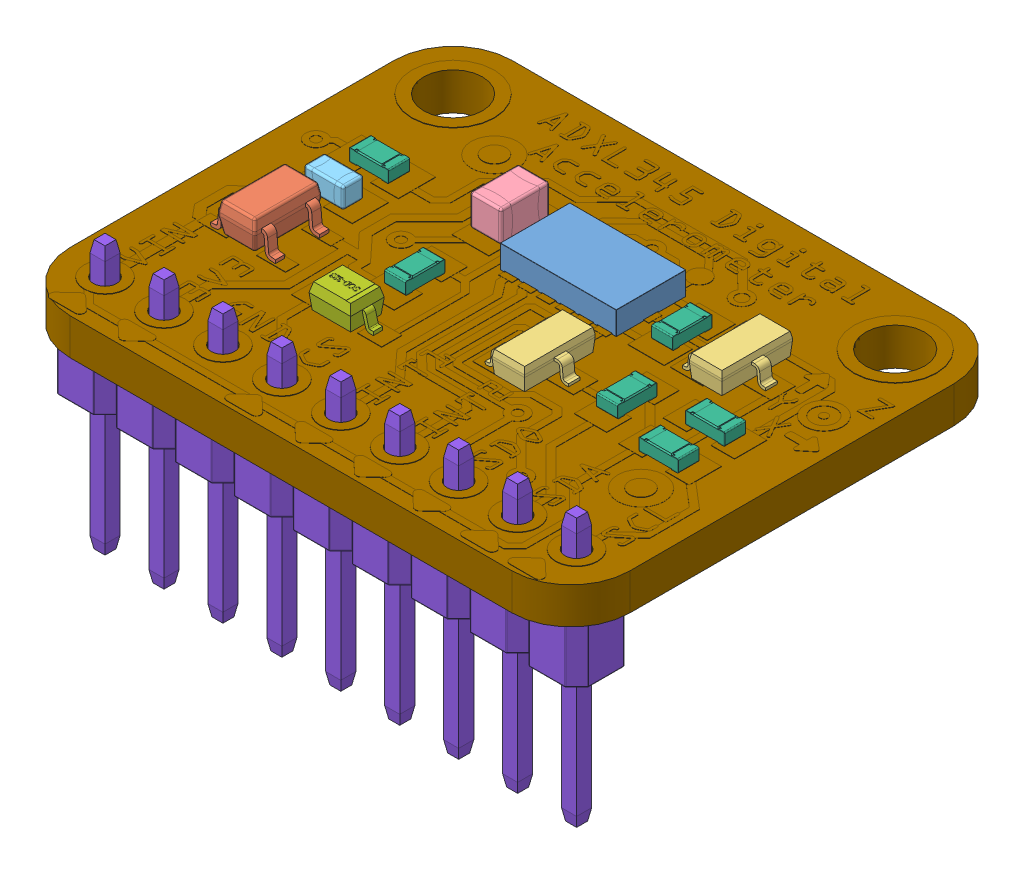
SolidWorks assembly ADXL345 Digital Accelerometer.step, configuration Default. Lengths in mm.
Overall size (24.13 11.59 19.05).
23 component instances, 9 part files, 0 mates.
Components (placement in the parent):
- 3x5 LGA Package.step-1: 3x5 LGA Package.step [Default] at (13.2372 0.005 -11.7916) x (0 0 1) z (-1 0 0) size (3 1 5)
- SOT-23-5.step-1: SOT-23-5.step [Default] at (1.7859 0.015 -5.313) size (2.8 1.45 2.9)
- SOT 23-3.step-1: SOT 23-3.step [Default] at (12.7718 0.115 -6.1282) x (0 0 1) z (-1 0 0) size (3.04 1.04 2.64)
- SOT 23-3.step-2: SOT 23-3.step [Default] at (17.1718 0.115 -10.2282) x (0 0 1) z (-1 0 0) size (3.04 1.04 2.64)
- Capacitor 0805 T1.35 BN.step-1: Capacitor 0805 T1.35 BN.step [Default] at (6.0126 0.685 -10.7496) x (0 0 -1) z (1 0 0) size (2.1 1.35 1.35)
- Capacitor 0603 T0.9 BN.step-1: Capacitor 0603 T0.9 BN.step [Default] at (1.8267 0.465 -8.4833) size (1.7 0.9 0.9)
- Resistor 0603.step-1: Resistor 0603.step [Default] at (0.9479 -0.035 -10.4764) size (1.7 0.55 0.9)
- Resistor 0603.step-2: Resistor 0603.step [Default] at (17.9907 -0.035 -5.913) size (1.7 0.55 0.9)
- Resistor 0603.step-3: Resistor 0603.step [Default] at (17.9907 -0.035 -7.913) size (1.7 0.55 0.9)
- Resistor 0603.step-4: Resistor 0603.step [Default] at (15.4553 -0.035 -5.7278) x (0 0 -1) z (1 0 0) size (1.7 0.55 0.9)
- Resistor 0603.step-5: Resistor 0603.step [Default] at (14.0899 -0.035 -9.4639) x (0 0 -1) z (1 0 0) size (1.7 0.55 0.9)
- Resistor 0603.step-6: Resistor 0603.step [Default] at (6.2819 -0.035 -5.7657) x (0 0 -1) z (1 0 0) size (1.7 0.55 0.9)
- SOD-323 Package.step-1: SOD-323 Package.step [Default] at (6.619 -0.005 -3.7923) x (0 0 -1) z (1 0 0) size (1.45 1.15 2.7)
- Male Pin Header.step-1: Male Pin Header.step [Default] at (-1.27 -4.13 -1.2719) size (2.54 11.54 2.54)
- Male Pin Header.step-2: Male Pin Header.step [Default] at (1.27 -4.13 -1.2719) size (2.54 11.54 2.54)
- Male Pin Header.step-3: Male Pin Header.step [Default] at (3.81 -4.13 -1.2719) size (2.54 11.54 2.54)
- Male Pin Header.step-4: Male Pin Header.step [Default] at (6.35 -4.13 -1.2719) size (2.54 11.54 2.54)
- Male Pin Header.step-5: Male Pin Header.step [Default] at (8.89 -4.13 -1.2719) size (2.54 11.54 2.54)
- Male Pin Header.step-6: Male Pin Header.step [Default] at (11.43 -4.13 -1.2719) size (2.54 11.54 2.54)
- Male Pin Header.step-7: Male Pin Header.step [Default] at (13.97 -4.13 -1.2719) size (2.54 11.54 2.54)
- Male Pin Header.step-8: Male Pin Header.step [Default] at (16.51 -4.13 -1.2719) size (2.54 11.54 2.54)
- Male Pin Header.step-9: Male Pin Header.step [Default] at (19.05 -4.13 -1.2719) size (2.54 11.54 2.54)
- ADXL345 Digital Accelerometer.step-1: ADXL345 Digital Accelerometer.step [Default] at origin size (24.13 1.61 19.05)
